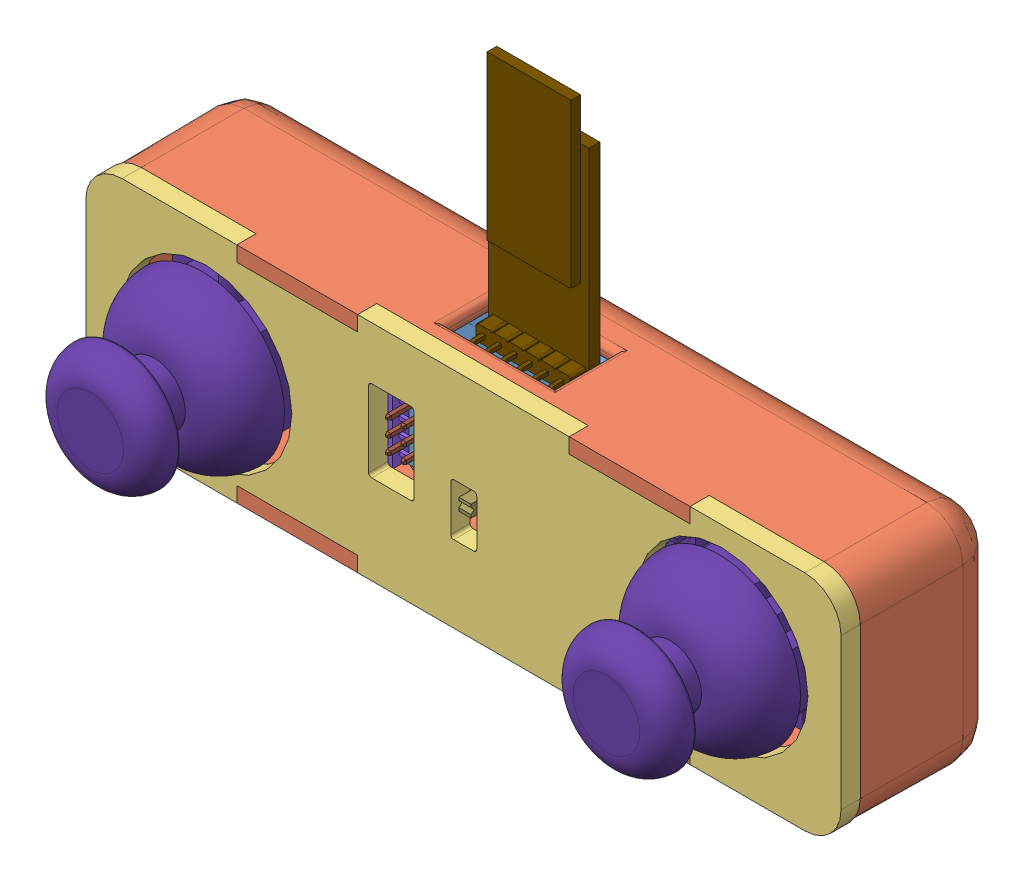
SolidWorks assembly BTCR_remote_complete_Assem, configuration Default. Lengths in mm.
Overall size (125 74.51 45.26).
39 component instances, 21 part files, 21 mates.
Components (placement in the parent):
- remotePCB-1: remotePCB [Default] at origin size (53.1 22.55 11.8)
  - PCB Component-1: PCB Component [Default] at origin size (53.1 22.55 11.8)
    - Board-1: Board [Default] at origin size (38 15 1.57)
    - 1K-1: 1K [Default] at (14.6 7.4 1.57) x (-1 0 0) z (0 0 1) size (2.11 1.36 0.61)
    - 1K-2: 1K [Default] at (29.5 9.2 1.57) x (0 1 0) z (0 0 1) size (2.11 1.36 0.61)
    - 1K-3: 1K [Default] at (31.8 9.2 1.57) x (0 1 0) z (0 0 1) size (2.11 1.36 0.61)
    - GREEN-1: GREEN [Default] at (29.5 13 1.57) x (0 -1 0) z (0 0 1) size (2 1.25 0.7)
      - base-1: base [Default] at (0.8 0 0) x (-1 0 0) z (0 0 1) size (0.4 1 0.3)
      - cover-1: cover [Default] at (0 0 0.3) size (1.4 1.25 0.4)
      - housing-1: housing [Default] at origin size (2 1.25 0.3)
      - marking-1: marking [Default] at (-0.8 0.525 0.26) size (0.4 0.48 0.04)
      - marking-2: marking [Default] at (-0.8 -0.525 0.3) x (1 0 0) z (0 0 -1) size (0.4 0.48 0.04)
      - base_2-1: base_2 [Default] at (-0.8 0 0) size (0.4 1 0.3)
    - GREEN-2: GREEN [Default] at (31.8 13 1.57) x (0 -1 0) z (0 0 1) size (2 1.25 0.7)
      - base-1: base [Default] at (0.8 0 0) x (-1 0 0) z (0 0 1) size (0.4 1 0.3)
      - cover-1: cover [Default] at (0 0 0.3) size (1.4 1.25 0.4)
      - housing-1: housing [Default] at origin size (2 1.25 0.3)
      - marking-1: marking [Default] at (-0.8 0.525 0.26) size (0.4 0.48 0.04)
      - marking-2: marking [Default] at (-0.8 -0.525 0.3) x (1 0 0) z (0 0 -1) size (0.4 0.48 0.04)
      - base_2-1: base_2 [Default] at (-0.8 0 0) size (0.4 1 0.3)
    - Thumbstick-1: Thumbstick [Default] at (2.7 12.6 1.57) x (0 -1 0) z (0 0 1) size (13.55 10.55 5.89)
    - Thumbstick-2: Thumbstick [Default] at (35.3 2.4 1.57) x (0 1 0) z (0 0 1) size (13.55 10.55 5.89)
    - ATtiny85V-1: ATtiny85V [Default] at (11.5 3.4 1.57) x (-1 0 0) z (0 0 1) size (8.26 5.35 2.16)
    - HM-10-1: HM-10 [Default] at (25.35 12.3 1.57) x (-1 0 0) z (0 0 1) size (16.09 10.55 5.89)
    - PTH VERT MALE-1: PTH VERT MALE [Default] at (5.73 8.06 1.57) x (0 1 0) z (0 0 1) size (7.62 4.83 11.43)
    - 300mA_30V-1: 300mA_30V [Default] at (19 6.1 1.57) size (4.3 8.6 11.5)
    - MCP1802 300mA_3.3V-1: MCP1802 300mA_3.3V [Default] at (26 5.1 1.57) size (3 3.05 1.45)
    - 1uF_25V-1: 1uF_25V [Default] at (5.3 2.4 1.57) x (0 1 0) z (0 0 1) size (2.21 1.36 0.96)
    - 1uF_25V-2: 1uF_25V [Default] at (29.5 5.1 1.57) x (0 -1 0) z (0 0 1) size (2.21 1.36 0.96)
    - 1uF_25V-3: 1uF_25V [Default] at (22.5 5.2 1.57) x (0 -1 0) z (0 0 1) size (2.21 1.36 0.96)
    - BATTERY_LIPO_2S-1: BATTERY_LIPO_2S [Default] at (24.3 9 0) x (1 0 0) z (0 0 -1) size (6 3.45 0.1)
    - JUMPER_SMD_3-PAD_NO_SILK-1: JUMPER_SMD_3-PAD_NO_SILK [Default] at (32.6 4.9 1.57) size (2.4 1.6 0.1)
    - JUMPER_SMD_3-PAD_NO_SILK-2: JUMPER_SMD_3-PAD_NO_SILK [Default] at (5.2 5.6 1.57) size (2.4 1.6 0.1)
- joy_stick_BTRC-1: joy_stick_BTRC [Default] at (44.559 -5.4963 -2.6863) x (1 0 0) z (0 -1 0) size (39.62 33.6 27.6)
- joy_stick_BTRC-2: joy_stick_BTRC [Default] at (-6.559 20.4963 -2.6863) x (-1 0 0) z (0 1 0) size (39.62 33.6 27.6)
- Bluetooth_RC-1: Bluetooth_RC [Default] at (18.9437 39.459 -2.0363) x (0 -1 0) z (0 0 1) size (47.2 16.6 8.1)
- Battery-1: Battery [Default] at (18.9437 7.6037 -13.7463) size (53.45 30.4 8.84)
- remote_case_bottom-1: remote_case_bottom [Default] at (18.9437 7.6037 -15.7463) size (125 37 26.18)
- remote_case_top-1: remote_case_top [Default] at (18.9437 7.6037 7.2537) size (125 37 3.17)
Mates (geometry in assembly coordinates):
- Coincident1: coincident: plane of remotePCB-1/PCB Component-1/Board-1 through (0 0 0) normal (0 0 1); plane of assembly through (0 0 0) normal (0 0 1)
- Coincident2: coincident: plane of remotePCB-1/PCB Component-1/Board-1 through (0 0 0) normal (0 1 0); plane of assembly through (0 0 0) normal (0 1 0)
- Coincident3: coincident: plane of remotePCB-1/PCB Component-1/Board-1 through (0 0 0) normal (1 0 0); plane of assembly through (0 0 0) normal (1 0 0)
- Coincident4: coincident: plane of ? through (45.309 12.9737 3.1637) normal (0 0 -1); plane of joy_stick_BTRC-1 through (46.884 12.9737 3.1637) normal (0 0 1)
- Coincident5: coincident: plane of ? through (45.309 12.9737 2.3763) normal (0 -1 0); plane of joy_stick_BTRC-1 through (43.234 12.9737 -0.4613) normal (0 1 0)
- Coincident6: coincident: plane of ? through (45.309 7.5 2.77) normal (1 0 0); plane of joy_stick_BTRC-1 through (45.309 13.8037 -1.0863) normal (-1 0 0)
- Coincident7: coincident: plane of ? through (-7.309 2.0263 2.3763) normal (0 1 0); plane of joy_stick_BTRC-2 through (-5.234 2.0263 -0.4613) normal (0 -1 0)
- Coincident8: coincident: plane of ? through (-7.309 2.0263 3.1637) normal (0 0 -1); plane of joy_stick_BTRC-2 through (-8.884 2.0263 3.1637) normal (0 0 1)
- Coincident9: coincident: plane of ? through (-7.309 7.5 2.77) normal (-1 0 0); plane of joy_stick_BTRC-2 through (-7.309 1.1963 -1.0863) normal (1 0 0)
- Coincident10: coincident: plane of ? through (25.7437 22.309 3.1637) normal (-1 0 0); plane of Bluetooth_RC-1 through (25.7437 16.409 2.5637) normal (1 0 0)
- Coincident12: coincident: plane of ? through (24.9563 22.309 3.1637) normal (0 0 -1); plane of Bluetooth_RC-1 through (25.1437 16.409 3.1637) normal (0 0 1)
- Coincident13: coincident: plane of ? through (19 22.309 2.77) normal (0 1 0); plane of Bluetooth_RC-1 through (26.7437 22.309 0.5637) normal (0 -1 0)
- Coincident14: coincident: plane of Bluetooth_RC-1 through (18.9437 39.459 -2.0363) normal (1 0 0); plane of Battery-1 through (18.9437 7.6037 -13.7463) normal (1 0 0)
- Coincident15: coincident: plane of Bluetooth_RC-1 through (26.7437 18.709 -4.9363) normal (0 0 -1); plane of Battery-1 through (2.5372 -1.4963 -4.9363) normal (0 0 1)
- Coincident17: coincident: plane of Battery-1 through (18.9437 7.6037 -13.7463) normal (0 0 -1); plane of remote_case_bottom-1 through (18.9437 7.6037 -13.7463) normal (0 0 1)
- Coincident18: coincident: plane of Bluetooth_RC-1 through (18.9437 39.459 -2.0363) normal (1 0 0); plane of remote_case_bottom-1 through (18.9437 7.6037 -15.7463) normal (1 0 0)
- Coincident19: coincident: line of joy_stick_BTRC-1 through (78.709 7.6037 -2.6863) axis (-1 0 0); plane of Battery-1 through (18.9437 7.6037 -13.7463) normal (0 1 0)
- Coincident20: coincident: line of joy_stick_BTRC-1 through (78.709 7.6037 -2.6863) axis (-1 0 0); plane of remote_case_bottom-1 through (18.9437 7.6037 -15.7463) normal (0 1 0)
- Coincident21: coincident: plane of remote_case_bottom-1 through (-43.5563 -10.8963 -13.7463) normal (0 -1 0); plane of remote_case_top-1 through (-43.5563 -10.8963 10.4287) normal (0 -1 0)
- Coincident22: coincident: plane of remote_case_bottom-1 through (-43.5563 -10.8963 -13.7463) normal (-1 0 0); plane of remote_case_top-1 through (-43.5563 -10.8963 10.4287) normal (-1 0 0)
- Coincident23: coincident: plane of remote_case_bottom-1 through (18.9437 7.6037 7.2537) normal (0 0 1); plane of remote_case_top-1 through (18.9437 7.6037 7.2537) normal (0 0 -1)
